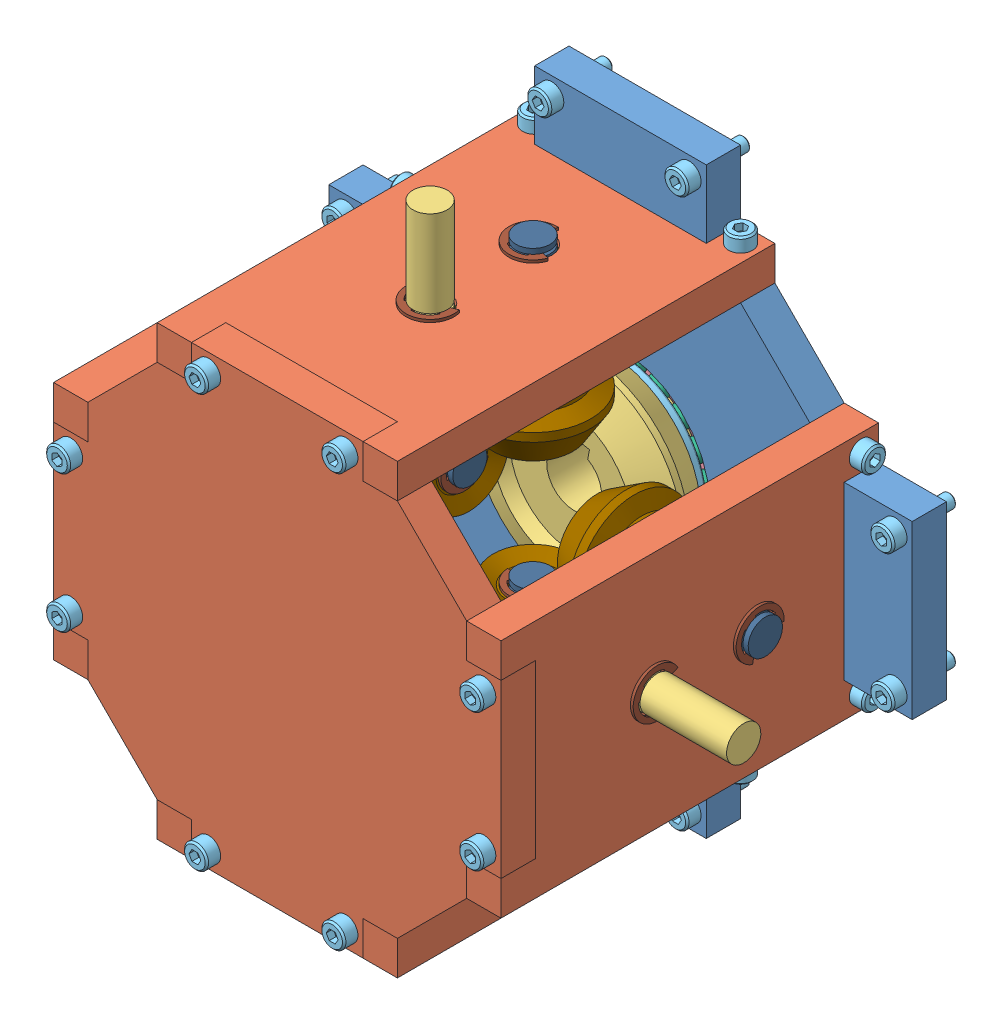
SolidWorks assembly gearbox_temp, configuration Default. Lengths in mm.
Overall size (182.78 182.78 120).
264 component instances, 23 part files, 0 mates.
Components (placement in the parent):
- gearbox_base-1: gearbox_base [Default] at origin size (170 170 10)
- gearbox_top-1: gearbox_top [Default] at (0 0 100) size (130.38 130.38 10)
- FHCWPB-2.0-3015-12(gear_ratio_1_2)-1: FHCWPB-2.0-3015-12(gear_ratio_1_2) [Default] at (0 0 2) x (-0.98037 0.197168 0) z (0.197168 0.98037 0) size (61.79 25 61.79)
- 51107-1: 51107 [Default] at (0 0 2) x (0.077785 0.99697 0) z (0.99697 -0.077785 0) size (52 12 52)
  - 51107 Housing washer-1: 51107 Housing washer [Default] at origin size (52 3.34 52)
  - 51107 Shaft washer-1: 51107 Shaft washer [Default] at (0 8.6667 0) x (0 1 0) z (0 0 1) size (3.34 52 52)
  - 51107 Ball-1: 51107 Ball [Default] at (-22.25 6 0) x (0 -1 0) z (0 0 1) size (6 6 6)
  - 51107 Ball-2: 51107 Ball [Default] at (-20.9082 6 7.6099) x (0 -1 0) z (0 0 1) size (6 6 6)
  - 51107 Ball-3: 51107 Ball [Default] at (-17.0445 6 14.302) x (0 -1 0) z (0 0 1) size (6 6 6)
  - 51107 Ball-4: 51107 Ball [Default] at (-11.125 6 19.2691) x (0 -1 0) z (0 0 1) size (6 6 6)
  - 51107 Ball-5: 51107 Ball [Default] at (-3.8637 6 21.912) x (0 -1 0) z (0 0 1) size (6 6 6)
  - 51107 Ball-6: 51107 Ball [Default] at (3.8637 6 21.912) x (0 -1 0) z (0 0 1) size (6 6 6)
  - 51107 Ball-7: 51107 Ball [Default] at (11.125 6 19.2691) x (0 -1 0) z (0 0 1) size (6 6 6)
  - 51107 Ball-8: 51107 Ball [Default] at (17.0445 6 14.302) x (0 -1 0) z (0 0 1) size (6 6 6)
  - 51107 Ball-9: 51107 Ball [Default] at (20.9082 6 7.6099) x (0 -1 0) z (0 0 1) size (6 6 6)
  - 51107 Ball-10: 51107 Ball [Default] at (22.25 6 0) x (0 -1 0) z (0 0 1) size (6 6 6)
  - 51107 Ball-11: 51107 Ball [Default] at (20.9082 6 -7.6099) x (0 -1 0) z (0 0 1) size (6 6 6)
  - 51107 Ball-12: 51107 Ball [Default] at (17.0445 6 -14.302) x (0 -1 0) z (0 0 1) size (6 6 6)
  - 51107 Ball-13: 51107 Ball [Default] at (11.125 6 -19.2691) x (0 -1 0) z (0 0 1) size (6 6 6)
  - 51107 Ball-14: 51107 Ball [Default] at (3.8637 6 -21.912) x (0 -1 0) z (0 0 1) size (6 6 6)
  - 51107 Ball-15: 51107 Ball [Default] at (-3.8637 6 -21.912) x (0 -1 0) z (0 0 1) size (6 6 6)
  - 51107 Ball-16: 51107 Ball [Default] at (-11.125 6 -19.2691) x (0 -1 0) z (0 0 1) size (6 6 6)
  - 51107 Ball-17: 51107 Ball [Default] at (-17.0445 6 -14.302) x (0 -1 0) z (0 0 1) size (6 6 6)
  - 51107 Ball-18: 51107 Ball [Default] at (-20.9082 6 -7.6099) x (0 -1 0) z (0 0 1) size (6 6 6)
- HCWGT-1.0-A-40-10-10-1: HCWGT-1.0-A-40-10-10 [Default] at (0 53.69 65.48) x (0.726146 0 0.687541) z (0 -1 0) size (42 42 10)
- HCWGT-1.0-A-20-10-10-1: HCWGT-1.0-A-20-10-10 [Default] at (0 53.69 35.48) x (-0.497102 0 0.867692) z (0 -1 0) size (22 22 10)
- FHCWPB-2.0-1530-10(gear_ratio_1_2)-1: FHCWPB-2.0-1530-10(gear_ratio_1_2) [Default] at (0 43.69 35.48) x (0.887504 0 0.4608) z (0.4608 0 -0.887504) size (33.58 25 33.58)
- gearbox_shaft1-1: gearbox_shaft1 [Default] at (0 18.39 35.48) x (-0.497102 0 0.867692) z (0 -1 0) size (10 10 49.3)
- METW-7-1: METW-7 [Default] at (0 19.89 35.48) x (0.760025 0 0.649894) z (0 -1 0) size (14 11.24 0.8)
- washer10_16_1-1: washer10_16_1 [Default] at (0 55.19 35.48) x (0.563896 0 -0.825846) z (0 -1 0) size (16 16 1.5)
- KKES04-030-1: KKES04-030 [Default] at (-4.8193 22.89 30.414) x (0 1 0) z (0.497102 0 -0.867692) size (30 4 4)
- METW-7-2: METW-7 [Default] at (0 65.39 35.48) x (0.563472 0 0.826135) z (0 -1 0) size (14 11.24 0.8)
- METW-7-3: METW-7 [Default] at (0 43.69 65.48) x (-0.416193 0 0.909276) z (0 1 0) size (14 11.24 0.8)
- washer10_16_1-2: washer10_16_1 [Default] at (0 55.49 65.48) x (-0.73472 0 -0.67837) z (0 -1 0) size (16 16 1.5)
- KKES04-008-1: KKES04-008 [Default] at (-6.0588 44.89 68.9701) x (0 1 0) z (-0.726146 0 -0.687541) size (8 4 4)
- 6000DDU-1: 6000DDU [Default] at (0 55.19 35.48) x (0 1 0) z (-0.055381 0 0.998465) size (8 26 26)
  - 6000DDU Outer ring-1: 6000DDU Outer ring [Default] at origin size (8 26 26)
  - 6000DDU Inner ring-1: 6000DDU Inner ring [Default] x (1 0 0) z (0 1 0) size (8 14.57 14.57)
  - 6000DDU Ball-1: 6000DDU Ball [Default] at (4 0 -9) x (1 0 0) z (0 1 0) size (4 4 4)
  - 6000DDU Ball-2: 6000DDU Ball [Default] at (4 4.1825 -7.9691) x (1 0 0) z (0 1 0) size (4 4 4)
  - 6000DDU Ball-3: 6000DDU Ball [Default] at (4 7.4069 -5.1126) x (1 0 0) z (0 1 0) size (4 4 4)
  - 6000DDU Ball-4: 6000DDU Ball [Default] at (4 8.9344 -1.0848) x (1 0 0) z (0 1 0) size (4 4 4)
  - 6000DDU Ball-5: 6000DDU Ball [Default] at (4 8.4151 3.1914) x (1 0 0) z (0 1 0) size (4 4 4)
  - 6000DDU Ball-6: 6000DDU Ball [Default] at (4 5.9681 6.7366) x (1 0 0) z (0 1 0) size (4 4 4)
  - 6000DDU Ball-7: 6000DDU Ball [Default] at (4 2.1538 8.7385) x (1 0 0) z (0 1 0) size (4 4 4)
  - 6000DDU Ball-8: 6000DDU Ball [Default] at (4 -2.1538 8.7385) x (1 0 0) z (0 1 0) size (4 4 4)
  - 6000DDU Ball-9: 6000DDU Ball [Default] at (4 -5.9681 6.7366) x (1 0 0) z (0 1 0) size (4 4 4)
  - 6000DDU Ball-10: 6000DDU Ball [Default] at (4 -8.4151 3.1914) x (1 0 0) z (0 1 0) size (4 4 4)
  - 6000DDU Ball-11: 6000DDU Ball [Default] at (4 -8.9344 -1.0848) x (1 0 0) z (0 1 0) size (4 4 4)
  - 6000DDU Ball-12: 6000DDU Ball [Default] at (4 -7.4069 -5.1126) x (1 0 0) z (0 1 0) size (4 4 4)
  - 6000DDU Ball-13: 6000DDU Ball [Default] at (4 -4.1825 -7.9691) x (1 0 0) z (0 1 0) size (4 4 4)
  - 6000DDU Shield1-1: 6000DDU Shield1 [Default] at (7.632 0 0) size (0.28 23 23)
  - 6000DDU Shield2-1: 6000DDU Shield2 [Default] at (0.368 0 0) x (-1 0 0) z (0 0 1) size (0.28 23 23)
- 6000DDU-2: 6000DDU [Default] at (0 55.49 65.48) x (0 1 0) z (0 0 1) size (8 26 26)
  - 6000DDU Outer ring-1: 6000DDU Outer ring [Default] at origin size (8 26 26)
  - 6000DDU Inner ring-1: 6000DDU Inner ring [Default] x (1 0 0) z (0 1 0) size (8 14.57 14.57)
  - 6000DDU Ball-1: 6000DDU Ball [Default] at (4 0 -9) x (1 0 0) z (0 1 0) size (4 4 4)
  - 6000DDU Ball-2: 6000DDU Ball [Default] at (4 4.1825 -7.9691) x (1 0 0) z (0 1 0) size (4 4 4)
  - 6000DDU Ball-3: 6000DDU Ball [Default] at (4 7.4069 -5.1126) x (1 0 0) z (0 1 0) size (4 4 4)
  - 6000DDU Ball-4: 6000DDU Ball [Default] at (4 8.9344 -1.0848) x (1 0 0) z (0 1 0) size (4 4 4)
  - 6000DDU Ball-5: 6000DDU Ball [Default] at (4 8.4151 3.1914) x (1 0 0) z (0 1 0) size (4 4 4)
  - 6000DDU Ball-6: 6000DDU Ball [Default] at (4 5.9681 6.7366) x (1 0 0) z (0 1 0) size (4 4 4)
  - 6000DDU Ball-7: 6000DDU Ball [Default] at (4 2.1538 8.7385) x (1 0 0) z (0 1 0) size (4 4 4)
  - 6000DDU Ball-8: 6000DDU Ball [Default] at (4 -2.1538 8.7385) x (1 0 0) z (0 1 0) size (4 4 4)
  - 6000DDU Ball-9: 6000DDU Ball [Default] at (4 -5.9681 6.7366) x (1 0 0) z (0 1 0) size (4 4 4)
  - 6000DDU Ball-10: 6000DDU Ball [Default] at (4 -8.4151 3.1914) x (1 0 0) z (0 1 0) size (4 4 4)
  - 6000DDU Ball-11: 6000DDU Ball [Default] at (4 -8.9344 -1.0848) x (1 0 0) z (0 1 0) size (4 4 4)
  - 6000DDU Ball-12: 6000DDU Ball [Default] at (4 -7.4069 -5.1126) x (1 0 0) z (0 1 0) size (4 4 4)
  - 6000DDU Ball-13: 6000DDU Ball [Default] at (4 -4.1825 -7.9691) x (1 0 0) z (0 1 0) size (4 4 4)
  - 6000DDU Shield1-1: 6000DDU Shield1 [Default] at (7.632 0 0) size (0.28 23 23)
  - 6000DDU Shield2-1: 6000DDU Shield2 [Default] at (0.368 0 0) x (-1 0 0) z (0 0 1) size (0.28 23 23)
- gearbox_side1-1: gearbox_side1 [Default] at (0 65.19 55) x (1 0 0) z (0 -1 0) size (70 110 10)
- gearbox_shaft2-1: gearbox_shaft2 [Default] at (0 41.39 65.48) x (0.726146 0 0.687541) z (0 -1 0) size (10 10 50)
- METW-7-4: METW-7 [Default] at (0 65.39 65.48) x (0.921614 0 0.388107) z (0 -1 0) size (14 11.24 0.8)
- 105.040-1: 105.040 [Default] at (30 47.65 5) size (6.5 8 6.5)
- 105.040-2: 105.040 [Default] at (-30 47.19 5) size (6.5 8 6.5)
- CBB4-16-1: CBB4-16 [Default] at (30 69.19 5) x (0 -1 0) z (0 0 1) size (20 7 7)
- CBB4-16-2: CBB4-16 [Default] at (-30 69.19 5) x (0 -1 0) z (0 0 1) size (20 7 7)
- CBB4-16-3: CBB4-16 [Default] at (20 80 14) x (0 0 -1) z (0 -1 0) size (20 7 7)
- CBB4-16-4: CBB4-16 [Default] at (-20 80 14) x (0 0 -1) z (0 -1 0) size (20 7 7)
- CBB4-16-5: CBB4-16 [Default] at (20 60.19 114) x (0 0 -1) z (0 -1 0) size (20 7 7)
- CBB4-16-6: CBB4-16 [Default] at (-20 60.19 114) x (0 0 -1) z (0 -1 0) size (20 7 7)
- 105.040-3: 105.040 [Default] at (20 60.19 92) x (1 0 0) z (0 -1 0) size (6.5 8 6.5)
- 105.040-4: 105.040 [Default] at (-20 60.19 92) x (1 0 0) z (0 -1 0) size (6.5 8 6.5)
- HCWGT-1.0-A-40-10-10-2: HCWGT-1.0-A-40-10-10 [Default] at (53.69 0 65.48) x (0 -0.726146 0.687541) z (-1 0 0) size (42 42 10)
- HCWGT-1.0-A-20-10-10-2: HCWGT-1.0-A-20-10-10 [Default] at (53.69 0 35.48) x (0 0.497102 0.867692) z (-1 0 0) size (22 22 10)
- FHCWPB-2.0-1530-10(gear_ratio_1_2)-2: FHCWPB-2.0-1530-10(gear_ratio_1_2) [Default] at (43.69 0 35.48) x (0 -0.887504 0.4608) z (0 -0.4608 -0.887504) size (33.58 25 33.58)
- gearbox_shaft1-2: gearbox_shaft1 [Default] at (18.39 0 35.48) x (0 0.497102 0.867692) z (-1 0 0) size (10 10 49.3)
- METW-7-5: METW-7 [Default] at (19.89 0 35.48) x (0 -0.760025 0.649894) z (-1 0 0) size (14 11.24 0.8)
- washer10_16_1-3: washer10_16_1 [Default] at (55.19 0 35.48) x (0 -0.563896 -0.825846) z (-1 0 0) size (16 16 1.5)
- KKES04-030-2: KKES04-030 [Default] at (22.89 4.8193 30.414) x (1 0 0) z (0 -0.497102 -0.867692) size (30 4 4)
- METW-7-6: METW-7 [Default] at (65.39 0 35.48) x (0 -0.563472 0.826135) z (-1 0 0) size (14 11.24 0.8)
- METW-7-7: METW-7 [Default] at (43.69 0 65.48) x (0 0.416193 0.909276) z (1 0 0) size (14 11.24 0.8)
- washer10_16_1-4: washer10_16_1 [Default] at (55.49 0 65.48) x (0 0.73472 -0.67837) z (-1 0 0) size (16 16 1.5)
- KKES04-008-2: KKES04-008 [Default] at (44.89 6.0588 68.9701) x (1 0 0) z (0 0.726146 -0.687541) size (8 4 4)
- 6000DDU-3: 6000DDU [Default] at (55.19 0 35.48) x (1 0 0) z (0 0.055381 0.998465) size (8 26 26)
  - 6000DDU Outer ring-1: 6000DDU Outer ring [Default] at origin size (8 26 26)
  - 6000DDU Inner ring-1: 6000DDU Inner ring [Default] x (1 0 0) z (0 1 0) size (8 14.57 14.57)
  - 6000DDU Ball-1: 6000DDU Ball [Default] at (4 0 -9) x (1 0 0) z (0 1 0) size (4 4 4)
  - 6000DDU Ball-2: 6000DDU Ball [Default] at (4 4.1825 -7.9691) x (1 0 0) z (0 1 0) size (4 4 4)
  - 6000DDU Ball-3: 6000DDU Ball [Default] at (4 7.4069 -5.1126) x (1 0 0) z (0 1 0) size (4 4 4)
  - 6000DDU Ball-4: 6000DDU Ball [Default] at (4 8.9344 -1.0848) x (1 0 0) z (0 1 0) size (4 4 4)
  - 6000DDU Ball-5: 6000DDU Ball [Default] at (4 8.4151 3.1914) x (1 0 0) z (0 1 0) size (4 4 4)
  - 6000DDU Ball-6: 6000DDU Ball [Default] at (4 5.9681 6.7366) x (1 0 0) z (0 1 0) size (4 4 4)
  - 6000DDU Ball-7: 6000DDU Ball [Default] at (4 2.1538 8.7385) x (1 0 0) z (0 1 0) size (4 4 4)
  - 6000DDU Ball-8: 6000DDU Ball [Default] at (4 -2.1538 8.7385) x (1 0 0) z (0 1 0) size (4 4 4)
  - 6000DDU Ball-9: 6000DDU Ball [Default] at (4 -5.9681 6.7366) x (1 0 0) z (0 1 0) size (4 4 4)
  - 6000DDU Ball-10: 6000DDU Ball [Default] at (4 -8.4151 3.1914) x (1 0 0) z (0 1 0) size (4 4 4)
  - 6000DDU Ball-11: 6000DDU Ball [Default] at (4 -8.9344 -1.0848) x (1 0 0) z (0 1 0) size (4 4 4)
  - 6000DDU Ball-12: 6000DDU Ball [Default] at (4 -7.4069 -5.1126) x (1 0 0) z (0 1 0) size (4 4 4)
  - 6000DDU Ball-13: 6000DDU Ball [Default] at (4 -4.1825 -7.9691) x (1 0 0) z (0 1 0) size (4 4 4)
  - 6000DDU Shield1-1: 6000DDU Shield1 [Default] at (7.632 0 0) size (0.28 23 23)
  - 6000DDU Shield2-1: 6000DDU Shield2 [Default] at (0.368 0 0) x (-1 0 0) z (0 0 1) size (0.28 23 23)
- 6000DDU-4: 6000DDU [Default] at (55.49 0 65.48) size (8 26 26)
  - 6000DDU Outer ring-1: 6000DDU Outer ring [Default] at origin size (8 26 26)
  - 6000DDU Inner ring-1: 6000DDU Inner ring [Default] x (1 0 0) z (0 1 0) size (8 14.57 14.57)
  - 6000DDU Ball-1: 6000DDU Ball [Default] at (4 0 -9) x (1 0 0) z (0 1 0) size (4 4 4)
  - 6000DDU Ball-2: 6000DDU Ball [Default] at (4 4.1825 -7.9691) x (1 0 0) z (0 1 0) size (4 4 4)
  - 6000DDU Ball-3: 6000DDU Ball [Default] at (4 7.4069 -5.1126) x (1 0 0) z (0 1 0) size (4 4 4)
  - 6000DDU Ball-4: 6000DDU Ball [Default] at (4 8.9344 -1.0848) x (1 0 0) z (0 1 0) size (4 4 4)
  - 6000DDU Ball-5: 6000DDU Ball [Default] at (4 8.4151 3.1914) x (1 0 0) z (0 1 0) size (4 4 4)
  - 6000DDU Ball-6: 6000DDU Ball [Default] at (4 5.9681 6.7366) x (1 0 0) z (0 1 0) size (4 4 4)
  - 6000DDU Ball-7: 6000DDU Ball [Default] at (4 2.1538 8.7385) x (1 0 0) z (0 1 0) size (4 4 4)
  - 6000DDU Ball-8: 6000DDU Ball [Default] at (4 -2.1538 8.7385) x (1 0 0) z (0 1 0) size (4 4 4)
  - 6000DDU Ball-9: 6000DDU Ball [Default] at (4 -5.9681 6.7366) x (1 0 0) z (0 1 0) size (4 4 4)
  - 6000DDU Ball-10: 6000DDU Ball [Default] at (4 -8.4151 3.1914) x (1 0 0) z (0 1 0) size (4 4 4)
  - 6000DDU Ball-11: 6000DDU Ball [Default] at (4 -8.9344 -1.0848) x (1 0 0) z (0 1 0) size (4 4 4)
  - 6000DDU Ball-12: 6000DDU Ball [Default] at (4 -7.4069 -5.1126) x (1 0 0) z (0 1 0) size (4 4 4)
  - 6000DDU Ball-13: 6000DDU Ball [Default] at (4 -4.1825 -7.9691) x (1 0 0) z (0 1 0) size (4 4 4)
  - 6000DDU Shield1-1: 6000DDU Shield1 [Default] at (7.632 0 0) size (0.28 23 23)
  - 6000DDU Shield2-1: 6000DDU Shield2 [Default] at (0.368 0 0) x (-1 0 0) z (0 0 1) size (0.28 23 23)
- gearbox_side1-2: gearbox_side1 [Default] at (65.19 0 55) x (0 -1 0) z (-1 0 0) size (70 110 10)
- gearbox_shaft2-2: gearbox_shaft2 [Default] at (41.39 0 65.48) x (0 -0.726146 0.687541) z (-1 0 0) size (10 10 50)
- METW-7-8: METW-7 [Default] at (65.39 0 65.48) x (0 -0.921614 0.388107) z (-1 0 0) size (14 11.24 0.8)
- 105.040-5: 105.040 [Default] at (47.65 -30 5) x (0 -1 0) z (0 0 1) size (6.5 8 6.5)
- 105.040-6: 105.040 [Default] at (47.19 30 5) x (0 -1 0) z (0 0 1) size (6.5 8 6.5)
- CBB4-16-7: CBB4-16 [Default] at (69.19 -30 5) x (-1 0 0) z (0 0 1) size (20 7 7)
- CBB4-16-8: CBB4-16 [Default] at (69.19 30 5) x (-1 0 0) z (0 0 1) size (20 7 7)
- CBB4-16-9: CBB4-16 [Default] at (80 -20 14) x (0 0 -1) z (-1 0 0) size (20 7 7)
- CBB4-16-10: CBB4-16 [Default] at (80 20 14) x (0 0 -1) z (-1 0 0) size (20 7 7)
- CBB4-16-11: CBB4-16 [Default] at (60.19 -20 114) x (0 0 -1) z (-1 0 0) size (20 7 7)
- CBB4-16-12: CBB4-16 [Default] at (60.19 20 114) x (0 0 -1) z (-1 0 0) size (20 7 7)
- 105.040-7: 105.040 [Default] at (60.19 -20 92) x (0 -1 0) z (-1 0 0) size (6.5 8 6.5)
- 105.040-8: 105.040 [Default] at (60.19 20 92) x (0 -1 0) z (-1 0 0) size (6.5 8 6.5)
- HCWGT-1.0-A-40-10-10-3: HCWGT-1.0-A-40-10-10 [Default] at (0 -53.69 65.48) x (-0.726146 0 0.687541) z (0 1 0) size (42 42 10)
- HCWGT-1.0-A-20-10-10-3: HCWGT-1.0-A-20-10-10 [Default] at (0 -53.69 35.48) x (0.497102 0 0.867692) z (0 1 0) size (22 22 10)
- FHCWPB-2.0-1530-10(gear_ratio_1_2)-3: FHCWPB-2.0-1530-10(gear_ratio_1_2) [Default] at (0 -43.69 35.48) x (-0.887504 0 0.4608) z (-0.4608 0 -0.887504) size (33.58 25 33.58)
- gearbox_shaft1-3: gearbox_shaft1 [Default] at (0 -18.39 35.48) x (0.497102 0 0.867692) z (0 1 0) size (10 10 49.3)
- METW-7-9: METW-7 [Default] at (0 -19.89 35.48) x (-0.760025 0 0.649894) z (0 1 0) size (14 11.24 0.8)
- washer10_16_1-5: washer10_16_1 [Default] at (0 -55.19 35.48) x (-0.563896 0 -0.825846) z (0 1 0) size (16 16 1.5)
- KKES04-030-3: KKES04-030 [Default] at (4.8193 -22.89 30.414) x (0 -1 0) z (-0.497102 0 -0.867692) size (30 4 4)
- METW-7-10: METW-7 [Default] at (0 -65.39 35.48) x (-0.563472 0 0.826135) z (0 1 0) size (14 11.24 0.8)
- METW-7-11: METW-7 [Default] at (0 -43.69 65.48) x (0.416193 0 0.909276) z (0 -1 0) size (14 11.24 0.8)
- washer10_16_1-6: washer10_16_1 [Default] at (0 -55.49 65.48) x (0.73472 0 -0.67837) z (0 1 0) size (16 16 1.5)
- KKES04-008-3: KKES04-008 [Default] at (6.0588 -44.89 68.9701) x (0 -1 0) z (0.726146 0 -0.687541) size (8 4 4)
- 6000DDU-5: 6000DDU [Default] at (0 -55.19 35.48) x (0 -1 0) z (0.055381 0 0.998465) size (8 26 26)
  - 6000DDU Outer ring-1: 6000DDU Outer ring [Default] at origin size (8 26 26)
  - 6000DDU Inner ring-1: 6000DDU Inner ring [Default] x (1 0 0) z (0 1 0) size (8 14.57 14.57)
  - 6000DDU Ball-1: 6000DDU Ball [Default] at (4 0 -9) x (1 0 0) z (0 1 0) size (4 4 4)
  - 6000DDU Ball-2: 6000DDU Ball [Default] at (4 4.1825 -7.9691) x (1 0 0) z (0 1 0) size (4 4 4)
  - 6000DDU Ball-3: 6000DDU Ball [Default] at (4 7.4069 -5.1126) x (1 0 0) z (0 1 0) size (4 4 4)
  - 6000DDU Ball-4: 6000DDU Ball [Default] at (4 8.9344 -1.0848) x (1 0 0) z (0 1 0) size (4 4 4)
  - 6000DDU Ball-5: 6000DDU Ball [Default] at (4 8.4151 3.1914) x (1 0 0) z (0 1 0) size (4 4 4)
  - 6000DDU Ball-6: 6000DDU Ball [Default] at (4 5.9681 6.7366) x (1 0 0) z (0 1 0) size (4 4 4)
  - 6000DDU Ball-7: 6000DDU Ball [Default] at (4 2.1538 8.7385) x (1 0 0) z (0 1 0) size (4 4 4)
  - 6000DDU Ball-8: 6000DDU Ball [Default] at (4 -2.1538 8.7385) x (1 0 0) z (0 1 0) size (4 4 4)
  - 6000DDU Ball-9: 6000DDU Ball [Default] at (4 -5.9681 6.7366) x (1 0 0) z (0 1 0) size (4 4 4)
  - 6000DDU Ball-10: 6000DDU Ball [Default] at (4 -8.4151 3.1914) x (1 0 0) z (0 1 0) size (4 4 4)
  - 6000DDU Ball-11: 6000DDU Ball [Default] at (4 -8.9344 -1.0848) x (1 0 0) z (0 1 0) size (4 4 4)
  - 6000DDU Ball-12: 6000DDU Ball [Default] at (4 -7.4069 -5.1126) x (1 0 0) z (0 1 0) size (4 4 4)
  - 6000DDU Ball-13: 6000DDU Ball [Default] at (4 -4.1825 -7.9691) x (1 0 0) z (0 1 0) size (4 4 4)
  - 6000DDU Shield1-1: 6000DDU Shield1 [Default] at (7.632 0 0) size (0.28 23 23)
  - 6000DDU Shield2-1: 6000DDU Shield2 [Default] at (0.368 0 0) x (-1 0 0) z (0 0 1) size (0.28 23 23)
- 6000DDU-6: 6000DDU [Default] at (0 -55.49 65.48) x (0 -1 0) z (0 0 1) size (8 26 26)
  - 6000DDU Outer ring-1: 6000DDU Outer ring [Default] at origin size (8 26 26)
  - 6000DDU Inner ring-1: 6000DDU Inner ring [Default] x (1 0 0) z (0 1 0) size (8 14.57 14.57)
  - 6000DDU Ball-1: 6000DDU Ball [Default] at (4 0 -9) x (1 0 0) z (0 1 0) size (4 4 4)
  - 6000DDU Ball-2: 6000DDU Ball [Default] at (4 4.1825 -7.9691) x (1 0 0) z (0 1 0) size (4 4 4)
  - 6000DDU Ball-3: 6000DDU Ball [Default] at (4 7.4069 -5.1126) x (1 0 0) z (0 1 0) size (4 4 4)
  - 6000DDU Ball-4: 6000DDU Ball [Default] at (4 8.9344 -1.0848) x (1 0 0) z (0 1 0) size (4 4 4)
  - 6000DDU Ball-5: 6000DDU Ball [Default] at (4 8.4151 3.1914) x (1 0 0) z (0 1 0) size (4 4 4)
  - 6000DDU Ball-6: 6000DDU Ball [Default] at (4 5.9681 6.7366) x (1 0 0) z (0 1 0) size (4 4 4)
  - 6000DDU Ball-7: 6000DDU Ball [Default] at (4 2.1538 8.7385) x (1 0 0) z (0 1 0) size (4 4 4)
  - 6000DDU Ball-8: 6000DDU Ball [Default] at (4 -2.1538 8.7385) x (1 0 0) z (0 1 0) size (4 4 4)
  - 6000DDU Ball-9: 6000DDU Ball [Default] at (4 -5.9681 6.7366) x (1 0 0) z (0 1 0) size (4 4 4)
  - 6000DDU Ball-10: 6000DDU Ball [Default] at (4 -8.4151 3.1914) x (1 0 0) z (0 1 0) size (4 4 4)
  - 6000DDU Ball-11: 6000DDU Ball [Default] at (4 -8.9344 -1.0848) x (1 0 0) z (0 1 0) size (4 4 4)
  - 6000DDU Ball-12: 6000DDU Ball [Default] at (4 -7.4069 -5.1126) x (1 0 0) z (0 1 0) size (4 4 4)
  - 6000DDU Ball-13: 6000DDU Ball [Default] at (4 -4.1825 -7.9691) x (1 0 0) z (0 1 0) size (4 4 4)
  - 6000DDU Shield1-1: 6000DDU Shield1 [Default] at (7.632 0 0) size (0.28 23 23)
  - 6000DDU Shield2-1: 6000DDU Shield2 [Default] at (0.368 0 0) x (-1 0 0) z (0 0 1) size (0.28 23 23)
- gearbox_side1-3: gearbox_side1 [Default] at (0 -65.19 55) x (-1 0 0) z (0 1 0) size (70 110 10)
- gearbox_shaft2-3: gearbox_shaft2 [Default] at (0 -41.39 65.48) x (-0.726146 0 0.687541) z (0 1 0) size (10 10 50)
- METW-7-12: METW-7 [Default] at (0 -65.39 65.48) x (-0.921614 0 0.388107) z (0 1 0) size (14 11.24 0.8)
- 105.040-9: 105.040 [Default] at (-30 -47.65 5) x (-1 0 0) z (0 0 1) size (6.5 8 6.5)
- 105.040-10: 105.040 [Default] at (30 -47.19 5) x (-1 0 0) z (0 0 1) size (6.5 8 6.5)
- CBB4-16-13: CBB4-16 [Default] at (-30 -69.19 5) x (0 1 0) z (0 0 1) size (20 7 7)
- CBB4-16-14: CBB4-16 [Default] at (30 -69.19 5) x (0 1 0) z (0 0 1) size (20 7 7)
- CBB4-16-15: CBB4-16 [Default] at (-20 -80 14) x (0 0 -1) z (0 1 0) size (20 7 7)
- CBB4-16-16: CBB4-16 [Default] at (20 -80 14) x (0 0 -1) z (0 1 0) size (20 7 7)
- CBB4-16-17: CBB4-16 [Default] at (-20 -60.19 114) x (0 0 -1) z (0 1 0) size (20 7 7)
- CBB4-16-18: CBB4-16 [Default] at (20 -60.19 114) x (0 0 -1) z (0 1 0) size (20 7 7)
- 105.040-11: 105.040 [Default] at (-20 -60.19 92) x (-1 0 0) z (0 1 0) size (6.5 8 6.5)
- 105.040-12: 105.040 [Default] at (20 -60.19 92) x (-1 0 0) z (0 1 0) size (6.5 8 6.5)
- HCWGT-1.0-A-40-10-10-4: HCWGT-1.0-A-40-10-10 [Default] at (-53.69 0 65.48) x (0 0.726146 0.687541) z (1 0 0) size (42 42 10)
- HCWGT-1.0-A-20-10-10-4: HCWGT-1.0-A-20-10-10 [Default] at (-53.69 0 35.48) x (0 -0.497102 0.867692) z (1 0 0) size (22 22 10)
- FHCWPB-2.0-1530-10(gear_ratio_1_2)-4: FHCWPB-2.0-1530-10(gear_ratio_1_2) [Default] at (-43.69 0 35.48) x (0 0.887504 0.4608) z (0 0.4608 -0.887504) size (33.58 25 33.58)
- gearbox_shaft1-4: gearbox_shaft1 [Default] at (-18.39 0 35.48) x (0 -0.497102 0.867692) z (1 0 0) size (10 10 49.3)
- METW-7-13: METW-7 [Default] at (-19.89 0 35.48) x (0 0.760025 0.649894) z (1 0 0) size (14 11.24 0.8)
- washer10_16_1-7: washer10_16_1 [Default] at (-55.19 0 35.48) x (0 0.563896 -0.825846) z (1 0 0) size (16 16 1.5)
- KKES04-030-4: KKES04-030 [Default] at (-22.89 -4.8193 30.414) x (-1 0 0) z (0 0.497102 -0.867692) size (30 4 4)
- METW-7-14: METW-7 [Default] at (-65.39 0 35.48) x (0 0.563472 0.826135) z (1 0 0) size (14 11.24 0.8)
- METW-7-15: METW-7 [Default] at (-43.69 0 65.48) x (0 -0.416193 0.909276) z (-1 0 0) size (14 11.24 0.8)
- washer10_16_1-8: washer10_16_1 [Default] at (-55.49 0 65.48) x (0 -0.73472 -0.67837) z (1 0 0) size (16 16 1.5)
- KKES04-008-4: KKES04-008 [Default] at (-44.89 -6.0588 68.9701) x (-1 0 0) z (0 -0.726146 -0.687541) size (8 4 4)
- 6000DDU-7: 6000DDU [Default] at (-55.19 0 35.48) x (-1 0 0) z (0 -0.055381 0.998465) size (8 26 26)
  - 6000DDU Outer ring-1: 6000DDU Outer ring [Default] at origin size (8 26 26)
  - 6000DDU Inner ring-1: 6000DDU Inner ring [Default] x (1 0 0) z (0 1 0) size (8 14.57 14.57)
  - 6000DDU Ball-1: 6000DDU Ball [Default] at (4 0 -9) x (1 0 0) z (0 1 0) size (4 4 4)
  - 6000DDU Ball-2: 6000DDU Ball [Default] at (4 4.1825 -7.9691) x (1 0 0) z (0 1 0) size (4 4 4)
  - 6000DDU Ball-3: 6000DDU Ball [Default] at (4 7.4069 -5.1126) x (1 0 0) z (0 1 0) size (4 4 4)
  - 6000DDU Ball-4: 6000DDU Ball [Default] at (4 8.9344 -1.0848) x (1 0 0) z (0 1 0) size (4 4 4)
  - 6000DDU Ball-5: 6000DDU Ball [Default] at (4 8.4151 3.1914) x (1 0 0) z (0 1 0) size (4 4 4)
  - 6000DDU Ball-6: 6000DDU Ball [Default] at (4 5.9681 6.7366) x (1 0 0) z (0 1 0) size (4 4 4)
  - 6000DDU Ball-7: 6000DDU Ball [Default] at (4 2.1538 8.7385) x (1 0 0) z (0 1 0) size (4 4 4)
  - 6000DDU Ball-8: 6000DDU Ball [Default] at (4 -2.1538 8.7385) x (1 0 0) z (0 1 0) size (4 4 4)
  - 6000DDU Ball-9: 6000DDU Ball [Default] at (4 -5.9681 6.7366) x (1 0 0) z (0 1 0) size (4 4 4)
  - 6000DDU Ball-10: 6000DDU Ball [Default] at (4 -8.4151 3.1914) x (1 0 0) z (0 1 0) size (4 4 4)
  - 6000DDU Ball-11: 6000DDU Ball [Default] at (4 -8.9344 -1.0848) x (1 0 0) z (0 1 0) size (4 4 4)
  - 6000DDU Ball-12: 6000DDU Ball [Default] at (4 -7.4069 -5.1126) x (1 0 0) z (0 1 0) size (4 4 4)
  - 6000DDU Ball-13: 6000DDU Ball [Default] at (4 -4.1825 -7.9691) x (1 0 0) z (0 1 0) size (4 4 4)
  - 6000DDU Shield1-1: 6000DDU Shield1 [Default] at (7.632 0 0) size (0.28 23 23)
  - 6000DDU Shield2-1: 6000DDU Shield2 [Default] at (0.368 0 0) x (-1 0 0) z (0 0 1) size (0.28 23 23)
- 6000DDU-8: 6000DDU [Default] at (-55.49 0 65.48) x (-1 0 0) z (0 0 1) size (8 26 26)
  - 6000DDU Outer ring-1: 6000DDU Outer ring [Default] at origin size (8 26 26)
  - 6000DDU Inner ring-1: 6000DDU Inner ring [Default] x (1 0 0) z (0 1 0) size (8 14.57 14.57)
  - 6000DDU Ball-1: 6000DDU Ball [Default] at (4 0 -9) x (1 0 0) z (0 1 0) size (4 4 4)
  - 6000DDU Ball-2: 6000DDU Ball [Default] at (4 4.1825 -7.9691) x (1 0 0) z (0 1 0) size (4 4 4)
  - 6000DDU Ball-3: 6000DDU Ball [Default] at (4 7.4069 -5.1126) x (1 0 0) z (0 1 0) size (4 4 4)
  - 6000DDU Ball-4: 6000DDU Ball [Default] at (4 8.9344 -1.0848) x (1 0 0) z (0 1 0) size (4 4 4)
  - 6000DDU Ball-5: 6000DDU Ball [Default] at (4 8.4151 3.1914) x (1 0 0) z (0 1 0) size (4 4 4)
  - 6000DDU Ball-6: 6000DDU Ball [Default] at (4 5.9681 6.7366) x (1 0 0) z (0 1 0) size (4 4 4)
  - 6000DDU Ball-7: 6000DDU Ball [Default] at (4 2.1538 8.7385) x (1 0 0) z (0 1 0) size (4 4 4)
  - 6000DDU Ball-8: 6000DDU Ball [Default] at (4 -2.1538 8.7385) x (1 0 0) z (0 1 0) size (4 4 4)
  - 6000DDU Ball-9: 6000DDU Ball [Default] at (4 -5.9681 6.7366) x (1 0 0) z (0 1 0) size (4 4 4)
  - 6000DDU Ball-10: 6000DDU Ball [Default] at (4 -8.4151 3.1914) x (1 0 0) z (0 1 0) size (4 4 4)
  - 6000DDU Ball-11: 6000DDU Ball [Default] at (4 -8.9344 -1.0848) x (1 0 0) z (0 1 0) size (4 4 4)
  - 6000DDU Ball-12: 6000DDU Ball [Default] at (4 -7.4069 -5.1126) x (1 0 0) z (0 1 0) size (4 4 4)
  - 6000DDU Ball-13: 6000DDU Ball [Default] at (4 -4.1825 -7.9691) x (1 0 0) z (0 1 0) size (4 4 4)
  - 6000DDU Shield1-1: 6000DDU Shield1 [Default] at (7.632 0 0) size (0.28 23 23)
  - 6000DDU Shield2-1: 6000DDU Shield2 [Default] at (0.368 0 0) x (-1 0 0) z (0 0 1) size (0.28 23 23)
- gearbox_side1-4: gearbox_side1 [Default] at (-65.19 0 55) x (0 1 0) z (1 0 0) size (70 110 10)
- gearbox_shaft2-4: gearbox_shaft2 [Default] at (-41.39 0 65.48) x (0 0.726146 0.687541) z (1 0 0) size (10 10 50)
- METW-7-16: METW-7 [Default] at (-65.39 0 65.48) x (0 0.921614 0.388107) z (1 0 0) size (14 11.24 0.8)
- 105.040-13: 105.040 [Default] at (-47.65 30 5) x (0 1 0) z (0 0 1) size (6.5 8 6.5)
- 105.040-14: 105.040 [Default] at (-47.19 -30 5) x (0 1 0) z (0 0 1) size (6.5 8 6.5)
- CBB4-16-19: CBB4-16 [Default] at (-69.19 30 5) size (20 7 7)
- CBB4-16-20: CBB4-16 [Default] at (-69.19 -30 5) size (20 7 7)
- CBB4-16-21: CBB4-16 [Default] at (-80 20 14) x (0 0 -1) z (1 0 0) size (20 7 7)
- CBB4-16-22: CBB4-16 [Default] at (-80 -20 14) x (0 0 -1) z (1 0 0) size (20 7 7)
- CBB4-16-23: CBB4-16 [Default] at (-60.19 20 114) x (0 0 -1) z (1 0 0) size (20 7 7)
- CBB4-16-24: CBB4-16 [Default] at (-60.19 -20 114) x (0 0 -1) z (1 0 0) size (20 7 7)
- 105.040-15: 105.040 [Default] at (-60.19 20 92) x (0 1 0) z (1 0 0) size (6.5 8 6.5)
- 105.040-16: 105.040 [Default] at (-60.19 -20 92) x (0 1 0) z (1 0 0) size (6.5 8 6.5)
